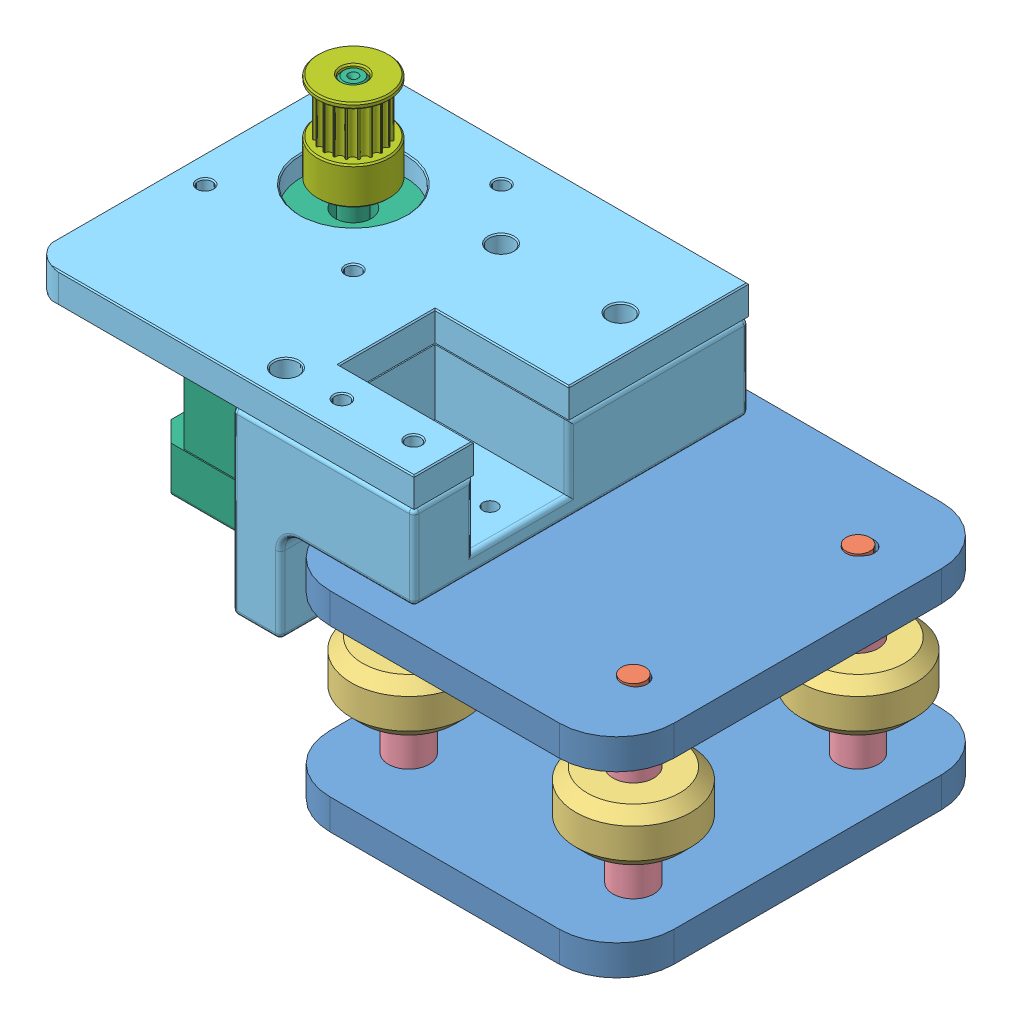
SolidWorks assembly v_wheel_carrage, configuration Default. Lengths in mm.
Overall size (130.25 87.66 80).
21 component instances, 7 part files, 18 mates.
Components (placement in the parent):
- v_wheel_carrage-1: v_wheel_carrage [Default] at (25.1366 33.0831 59.2346) size (72 6.35 80)
- shaft-2: shaft [Default] at (1.3866 77.1829 82.9846) x (-0.993132 0 0.117003) z (0.117003 0 0.993132) size (5 43.7 5)
- v_wheel-2: v_wheel [Default] at (1.3866 60.4331 82.9846) x (0.968872 0 -0.247564) z (0 1 0) size (24 24 11)
- spacer-4: spacer [Default] at (1.3866 70.4331 82.9846) x (1 0 0) z (0 -1 0) size (8.5 8.5 10)
- spacer-5: spacer [Default] at (1.3866 49.4331 82.9846) x (1 0 0) z (0 -1 0) size (8.5 8.5 10)
- v_wheel_carrage-2: v_wheel_carrage [m_plate] at (25.1366 70.4331 59.2346) size (72 6.35 80)
- v_wheel-7: v_wheel [Default] at (1.3866 60.4331 35.9846) x (0.968872 0 -0.247564) z (0 1 0) size (24 24 11)
- v_wheel-8: v_wheel [Default] at (48.3866 60.4331 82.9846) x (0.968872 0 -0.247564) z (0 1 0) size (24 24 11)
- v_wheel-9: v_wheel [Default] at (48.3866 60.4331 35.9846) x (0.968872 0 -0.247564) z (0 1 0) size (24 24 11)
- spacer-6: spacer [Default] at (1.3866 70.4331 35.9846) x (1 0 0) z (0 -1 0) size (8.5 8.5 10)
- spacer-7: spacer [Default] at (48.3866 70.4331 82.9846) x (1 0 0) z (0 -1 0) size (8.5 8.5 10)
- spacer-8: spacer [Default] at (48.3866 70.4331 35.9846) x (1 0 0) z (0 -1 0) size (8.5 8.5 10)
- spacer-9: spacer [Default] at (1.3866 49.4331 35.9846) x (1 0 0) z (0 -1 0) size (8.5 8.5 10)
- spacer-10: spacer [Default] at (48.3866 49.4331 82.9846) x (1 0 0) z (0 -1 0) size (8.5 8.5 10)
- spacer-11: spacer [Default] at (48.3866 49.4331 35.9846) x (1 0 0) z (0 -1 0) size (8.5 8.5 10)
- shaft-8: shaft [Default] at (1.3866 77.1829 35.9846) x (-0.993132 0 0.117003) z (0.117003 0 0.993132) size (5 43.7 5)
- shaft-9: shaft [Default] at (48.3866 77.1829 82.9846) x (-0.993132 0 0.117003) z (0.117003 0 0.993132) size (5 43.7 5)
- shaft-10: shaft [Default] at (48.3866 77.1829 35.9846) x (-0.993132 0 0.117003) z (0.117003 0 0.993132) size (5 43.7 5)
- x_axis_motor_mount_V1-1: x_axis_motor_mount_V1 [V_sus.1] at (13.1366 76.7831 93.6346) x (-1 0 0) z (0 0 -1) size (80.4 43.98 70)
- 6627T91_Stepper Motor-1: 6627T91_Stepper Motor [6627T91] at (-46.0634 83.4211 47.1346) x (1 0 0) z (0 1 0) size (42.4 43.16 74.04)
- 3684N13_Corrosion-Resistant HTD Timing Belt Pulley-1: 3684N13_Corrosion-Resistant HTD Timing Belt Pulley [3684N13] at (-46.0634 109.5387 47.1346) x (0.899592 0 -0.436731) z (0 1 0) size (18 18 18)
Mates (geometry in assembly coordinates):
- Concentric11: concentric aligned: cylinder of v_wheel_carrage-1 through (1.3866 33.0831 82.9846) axis (0 1 0) radius 2.4; cylinder of shaft-2 through (1.3866 33.4829 82.9846) axis (0 1 0) radius 2.5
- Concentric71: concentric aligned: cylinder of shaft-2 through (1.3866 33.4829 82.9846) axis (0 1 0) radius 2.5; cylinder of v_wheel-2 through (1.3866 60.4331 82.9846) axis (0 1 0) radius 2.5
- Concentric131: concentric aligned: cylinder of shaft-2 through (1.3866 33.4829 82.9846) axis (0 1 0) radius 2.5; cylinder of spacer-4 through (1.3866 60.4331 82.9846) axis (0 1 0) radius 2.75
- Concentric141: concentric aligned: cylinder of shaft-2 through (1.3866 33.4829 82.9846) axis (0 1 0) radius 2.5; cylinder of spacer-5 through (1.3866 39.4331 82.9846) axis (0 1 0) radius 2.75
- Coincident1: coincident anti-aligned: plane of v_wheel-2 through (3.8088 60.4331 82.3657) normal (0 1 0); plane of spacer-4 through (1.3866 60.4331 82.9846) normal (0 -1 0)
- Coincident2: coincident anti-aligned: plane of v_wheel-2 through (10.7362 49.4331 80.5956) normal (0 -1 0); plane of spacer-5 through (1.3866 49.4331 82.9846) normal (0 1 0)
- Coincident3: coincident anti-aligned: plane of v_wheel_carrage-1 through (49.1366 39.4331 31.2346) normal (0 1 0); plane of spacer-5 through (1.3866 39.4331 82.9846) normal (0 -1 0)
- Parallel1: parallel aligned: plane of v_wheel_carrage-1 through (1.1366 39.4331 99.2346) normal (0 0 1); plane of v_wheel_carrage-2 through (1.1366 76.7831 99.2346) normal (0 0 1)
- Coincident5: coincident anti-aligned: plane of spacer-4 through (1.3866 70.4331 82.9846) normal (0 1 0); plane of v_wheel_carrage-2 through (49.1366 70.4331 31.2346) normal (0 -1 0)
- Coincident6: coincident anti-aligned: plane of v_wheel_carrage-2 through (49.1366 76.7831 31.2346) normal (0 1 0); plane of x_axis_motor_mount_V1-1 through (-14.8634 76.7831 23.6346) normal (0 -1 0)
- Coincident7: coincident aligned: plane of v_wheel_carrage-1 through (61.1366 39.4331 87.2346) normal (1 0 0); plane of v_wheel_carrage-2 through (61.1366 76.7831 87.2346) normal (1 0 0)
- Coincident8: coincident aligned: plane of v_wheel_carrage-1 through (1.1366 39.4331 19.2346) normal (0 0 -1); plane of v_wheel_carrage-2 through (1.1366 76.7831 19.2346) normal (0 0 -1)
- Concentric143: concentric anti-aligned: cylinder of v_wheel_carrage-2 through (6.6366 70.4331 71.2346) axis (0 1 0) radius 1.5; cylinder of x_axis_motor_mount_V1-1 through (6.6366 100.7581 71.2346) axis (0 -1 0) radius 1.5
- Concentric144: concentric anti-aligned: cylinder of v_wheel_carrage-2 through (-8.3634 70.4331 71.2346) axis (0 1 0) radius 1.5; cylinder of x_axis_motor_mount_V1-1 through (-8.3634 100.7581 71.2346) axis (0 -1 0) radius 1.5
- Coincident9: coincident anti-aligned: plane of x_axis_motor_mount_V1-1 through (-24.8634 94.4081 23.6346) normal (0 -1 0); plane of 6627T91_Stepper Motor-1 through (-46.0634 94.4081 47.1346) normal (0 1 0)
- Concentric145: concentric aligned: cylinder of x_axis_motor_mount_V1-1 through (-30.5634 100.7581 31.6346) axis (0 -1 0) radius 1.5; circle of 6627T91_Stepper Motor-1
- Concentric146: concentric aligned: cylinder of x_axis_motor_mount_V1-1 through (-61.5634 100.7581 62.6346) axis (0 -1 0) radius 1.5; circle of 6627T91_Stepper Motor-1
- Concentric147: concentric anti-aligned: cylinder of 6627T91_Stepper Motor-1 through (-46.0634 120.4401 47.1346) axis (0 -1 0) radius 2.5; cylinder of 3684N13_Corrosion-Resistant HTD Timing Belt Pulley-1 through (-46.0634 120.7387 47.1346) axis (0 1 0) radius 2.5
